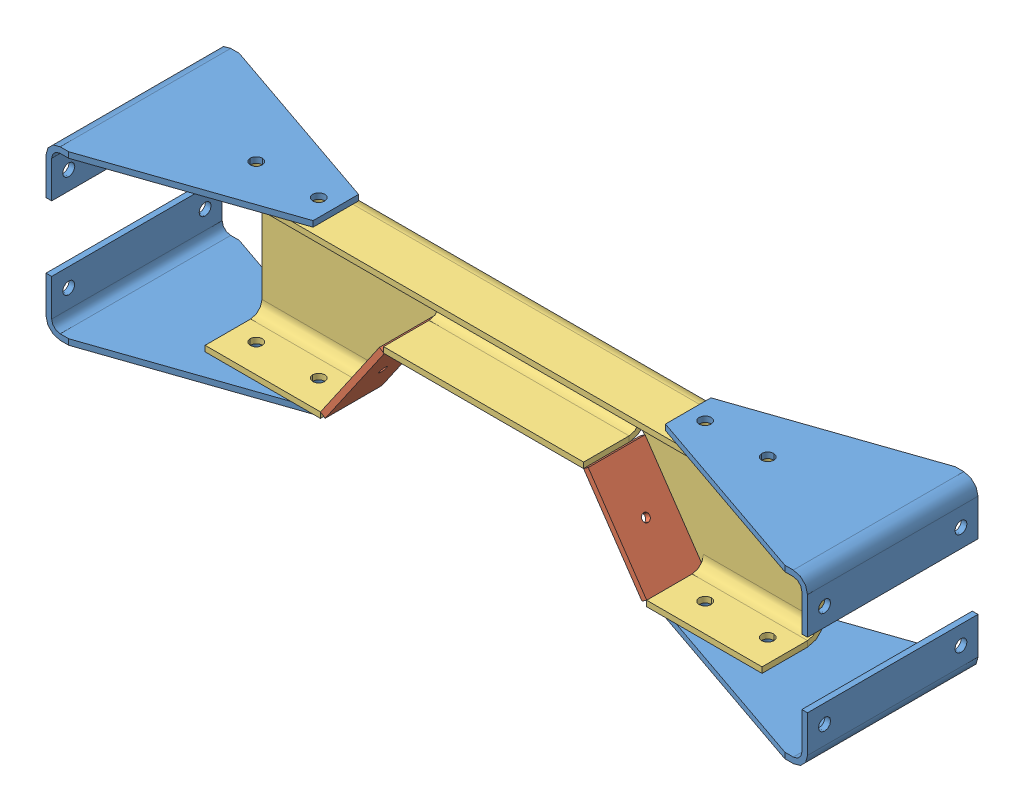
SolidWorks assembly SUB-1700-085, configuration No Fasteners. Lengths in mm.
Overall size (850.9 187.32 190.5).
24 component instances, 5 part files, 47 mates.
Components (placement in the parent):
- XXXXFLN8Y-5: XXXXFLN8Y [0813FLN8Y] at (-285.75 -6.35 -31.75) x (-0.776123 0 0.630581) z (0 -1 0) (suppressed, hidden)
- XXXXFLN8Y-3: XXXXFLN8Y [0813FLN8Y] at (-215.9 -6.35 -31.75) x (0.551583 0 0.83412) z (0 -1 0) (suppressed, hidden)
- XXXXFLN8Y-7: XXXXFLN8Y [0813FLN8Y] at (215.9 -6.35 -31.75) x (0.925888 0 0.377797) z (0 -1 0) (suppressed, hidden)
- XXXXFLN8Y-2: XXXXFLN8Y [0813FLN8Y] at (-215.9 -168.275 -31.75) x (0.973587 0 -0.228318) z (0 1 0) (suppressed, hidden)
- XXXXFLN8Y-8: XXXXFLN8Y [0813FLN8Y] at (285.75 -6.35 -31.75) x (0.857239 0 0.514919) z (0 -1 0) (suppressed, hidden)
- XXXXFLN8Y-4: XXXXFLN8Y [0813FLN8Y] at (285.75 -168.275 -31.75) x (0.247589 0 0.968865) z (0 1 0) (suppressed, hidden)
- XXXXFLN8Y-1: XXXXFLN8Y [0813FLN8Y] at (-285.75 -168.275 -31.75) x (-0.370867 0 -0.928686) z (0 1 0) (suppressed, hidden)
- XXXXFLN8Y-6: XXXXFLN8Y [0813FLN8Y] at (215.9 -168.275 -31.75) x (-0.753315 0 -0.65766) z (0 1 0) (suppressed, hidden)
- 08130XXXFH8Y-10: 08130XXXFH8Y [08130125FH8Y] at (-285.75 6.35 -31.75) x (-0.31018 0 -0.950678) z (0 1 0) (suppressed, hidden)
- 08130XXXFH8Y-11: 08130XXXFH8Y [08130125FH8Y] at (-215.9 6.35 -31.75) x (0.102236 0 -0.99476) z (0 1 0) (suppressed, hidden)
- 08130XXXFH8Y-15: 08130XXXFH8Y [08130125FH8Y] at (215.9 -180.975 -31.75) x (-0.580417 0 0.81432) z (0 -1 0) (suppressed, hidden)
- 08130XXXFH8Y-9: 08130XXXFH8Y [08130125FH8Y] at (-215.9 -180.975 -31.75) x (0.269191 0 0.963087) z (0 -1 0) (suppressed, hidden)
- 08130XXXFH8Y-13: 08130XXXFH8Y [08130125FH8Y] at (285.75 -180.975 -31.75) x (0.991585 0 -0.129459) z (0 -1 0) (suppressed, hidden)
- 08130XXXFH8Y-16: 08130XXXFH8Y [08130125FH8Y] at (285.75 6.35 -31.75) x (0.773261 0 0.634088) z (0 1 0) (suppressed, hidden)
- 08130XXXFH8Y-14: 08130XXXFH8Y [08130125FH8Y] at (215.9 6.35 -31.75) x (-0.04352 0 -0.999053) z (0 1 0) (suppressed, hidden)
- 08130XXXFH8Y-12: 08130XXXFH8Y [08130125FH8Y] at (-285.75 -180.975 -31.75) x (0.973807 0 -0.227376) z (0 -1 0) (suppressed, hidden)
- 2517-CC2-1: 2517-CC2 [2517-CC2-001] at (-425.45 6.35 -31.75)
- 2517-CC2-2: 2517-CC2 [2517-CC2-001] at (425.45 6.35 -31.75) x (-1 0 0) z (0 0 -1)
- 2517-CC2-3: 2517-CC2 [2517-CC2-001] at (425.45 -180.975 -31.75) x (-1 0 0) z (0 0 1)
- 2517-CC2-4: 2517-CC2 [2517-CC2-001] at (-425.45 -180.975 -31.75) x (1 0 0) z (0 0 -1)
- 2575-CC2-2: 2575-CC2 [Default] at (0 0 -69.85) size (622.3 174.62 69.85)
  - 2575-CC2 DTL2-1: 2575-CC2 DTL2 [Default] at (-182.245 -168.275 69.85) x (0.568105 0.822956 0) z (-0.822956 0.568105 0) size (115.92 63.5 6.35)
  - 2575-CC2 DTL2-2: 2575-CC2 DTL2 [Default] at (176.999 -171.853 69.85) x (-0.563461 0.826143 0) z (-0.826143 -0.563461 0) size (115.92 63.5 6.35)
  - 2575-CC2 DTL1-1: 2575-CC2 DTL1 [FLAT] at origin size (622.3 174.62 69.85)
Mates (geometry in assembly coordinates):
- Coincident67: coincident aligned: plane of 2575-CC2-2/2575-CC2 DTL1-1 through (0 0 -69.85) normal (0 1 0)
- Coincident68: coincident aligned: 
- Distance3: distance = 311.15 mm aligned: 
- Concentric1: concentric anti-aligned: 
- Concentric2: concentric anti-aligned: 
- Coincident70: coincident anti-aligned: 
- Concentric3: concentric aligned: 
- Concentric4: concentric aligned: 
- Concentric5: concentric anti-aligned: 
- Concentric6: concentric anti-aligned: 
- Coincident71: coincident anti-aligned: 
- Coincident72: coincident anti-aligned: 
- Coincident73: coincident anti-aligned: 
- Coincident74: coincident anti-aligned: 
- Concentric7: concentric aligned: 
- Concentric8: concentric aligned: 
- Concentric9: concentric anti-aligned: 
- Concentric10: concentric anti-aligned: 
- Coincident75: coincident anti-aligned: 
- Concentric11: concentric anti-aligned: 
- Concentric12: concentric anti-aligned: 
- Coincident76: coincident anti-aligned: 
- Coincident77: coincident anti-aligned: 
- Coincident78: coincident anti-aligned: 
- Coincident79: coincident anti-aligned: 
- Concentric14: concentric anti-aligned: 
- Concentric15: concentric anti-aligned: 
- Concentric16: concentric anti-aligned: 
- Coincident80: coincident anti-aligned: 
- Coincident81: coincident anti-aligned: 
- Coincident82: coincident anti-aligned: 
- Concentric17: concentric anti-aligned: 
- Concentric18: concentric anti-aligned: 
- Concentric19: concentric anti-aligned: 
- Coincident83: coincident anti-aligned: 
- Coincident84: coincident anti-aligned: 
- Concentric20: concentric anti-aligned: 
- Concentric21: concentric anti-aligned: 
- Coincident85: coincident anti-aligned: 
- Concentric22: concentric aligned: 
- Concentric23: concentric aligned: 
- Concentric24: concentric anti-aligned: 
- Concentric25: concentric anti-aligned: 
- Coincident86: coincident anti-aligned: 
- Coincident87: coincident anti-aligned: 
- Coincident88: coincident anti-aligned: 
- Coincident89: coincident anti-aligned: 
